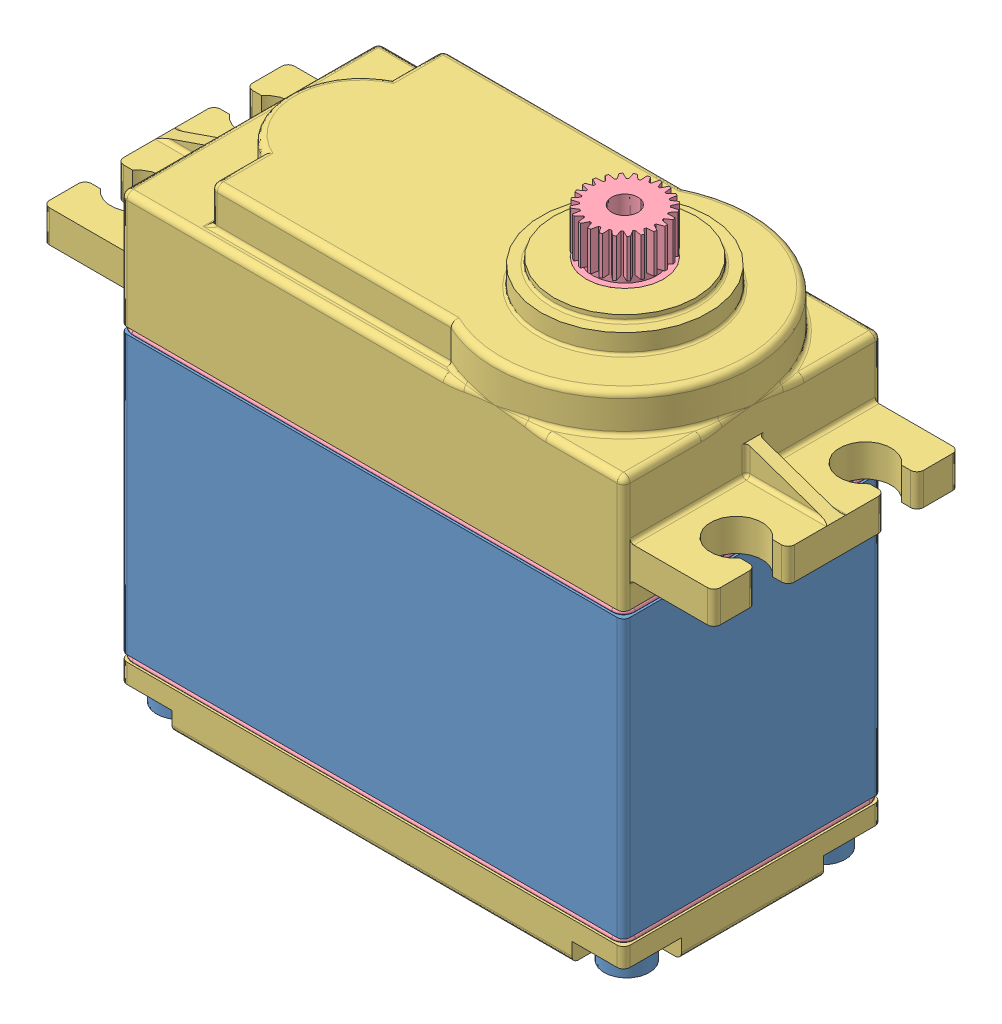
SolidWorks assembly РМ4, configuration По умолчанию. Lengths in mm.
Overall size (52 43 23.81).
64 component instances, 28 part files, 82 mates.
Components (placement in the parent):
- Корпус-2: Корпус [По умолчанию] at origin size (39 28 20)
- Плата-1: Плата [По умолчанию] at (0 -10.5 0) x (-1 0 0) z (0 0 -1) size (37.4 1 18.4)
- Крышка-1: Крышка [По умолчанию] at (0 -13 0) x (-1 0 0) z (0 0 1) size (39 4 20)
- G1-1: G1 [Spur01] at (9.6 15.75 0) x (0.004766 0 0.999989) z (0 1 0) size (17.2 17.2 15.5)
- G2-1: G2 [Spur02] at (-1.2 16.75 0) x (-0.940242 0 0.340506) z (0 1 0) size (6 6 7)
- G3-1: G3 [G3] at (-1.2 19.25 0) x (0.340506 0 0.940242) z (0 1 0) size (13.2 13.2 2)
- G4-1: G4 [G4] at (-9.9 18.5 0) x (-0.495475 0 0.868622) z (0 -1 0) size (5.4 5.4 4)
- G5-1: G5 [G6] at (-9.9 12.5 0) x (0.495475 0 -0.868622) z (0 1 0) size (14.4 14.4 5.5)
- G6-1: G6 [G5] at (-1.2 12 0) x (0.105267 0 -0.994444) z (0 -1 0) size (4.2 4.2 2.5)
- G7-1: G7 [G7] at (-1.2 11.25 0) x (0.994444 0 0.105267) z (0 -1 0) size (15 15 1)
- G8-1: G8 [П8] at (-9.7 11.25 0) x (0.946769 0 0.321915) z (0 -1 0) size (3 3 1)
- Пласт2-1: Пласт2 [По умолчанию] at (9.6 16.5 0) x (0.004766 0 0.999989) z (0.999989 0 -0.004766) size (10 3.05 9.77)
- Пласт1-1: Пласт1 [По умолчанию] at (9.6 14.5 0) x (-0.004766 0 -0.999989) z (0.999989 0 -0.004766) size (7 1.5 9.77)
- Ось-1: Ось [По умолчанию] at (-1.2 15.75 0) x (0.961755 0 0.273911) z (0.273911 0 -0.961755) size (1.5 12.5 1.5)
- Ось1-1: Ось1 [По умолчанию] at (-9.9 18.75 0) x (0.831133 0 0.556074) z (-0.556074 0 0.831133) size (1.5 6.5 1.5)
- Подшипник_1-1: Подшипник_1 [По умолчанию] at (9.6 13.5 0) size (14.01 2 14.01)
  - Вн_кольцо-1: Вн_кольцо [По умолчанию] at origin size (7 2 7)
  - Нар_кольцо-2: Нар_кольцо [По умолчанию] x (0.605705 0 -0.795689) z (0.795689 0 0.605705) size (10 2 10)
  - Шарик-1: Шарик [По умолчанию] at (-3.9953 0 0.1946) size (1.5 1.5 1.5)
  - Шарик-2: Шарик [По умолчанию] at (-3.3466 0 -2.1909) x (0.809017 0 0.587785) z (-0.587785 0 0.809017) size (1.5 1.5 1.5)
  - Шарик-3: Шарик [По умолчанию] at (-1.4197 0 -3.7396) x (0.309017 0 0.951057) z (-0.951057 0 0.309017) size (1.5 1.5 1.5)
  - Шарик-4: Шарик [По умолчанию] at (1.0495 0 -3.8599) x (-0.309017 0 0.951057) z (-0.951057 0 -0.309017) size (1.5 1.5 1.5)
  - Шарик-5: Шарик [По умолчанию] at (3.1179 0 -2.5058) x (-0.809017 0 0.587785) z (-0.587785 0 -0.809017) size (1.5 1.5 1.5)
  - Шарик-6: Шарик [По умолчанию] at (3.9953 0 -0.1946) x (-1 0 0) z (0 0 -1) size (1.5 1.5 1.5)
  - Шарик-7: Шарик [По умолчанию] at (3.3466 0 2.1909) x (-0.809017 0 -0.587785) z (0.587785 0 -0.809017) size (1.5 1.5 1.5)
  - Шарик-8: Шарик [По умолчанию] at (1.4197 0 3.7396) x (-0.309017 0 -0.951057) z (0.951057 0 -0.309017) size (1.5 1.5 1.5)
  - Шарик-9: Шарик [По умолчанию] at (-1.0495 0 3.8599) x (0.309017 0 -0.951057) z (0.951057 0 0.309017) size (1.5 1.5 1.5)
  - Шарик-10: Шарик [По умолчанию] at (-3.1179 0 2.5058) x (0.809017 0 -0.587785) z (0.587785 0 0.809017) size (1.5 1.5 1.5)
- Винт-1: Винт [По умолчанию] at (17.35 0.5 7.6) x (0.946284 0 0.323336) z (0.323336 0 -0.946284) size (3.5 31 3.5)
- Упл_кольцо-1: Упл_кольцо [По умолчанию] at (17.35 -13.5 7.6) x (0.852696 0 0.522408) z (-0.522408 0 0.852696) size (3.2 0.5 3.2)
- Винт-2: Винт [По умолчанию] at (17.35 0 -7.6) x (0.966388 0 0.257088) z (0.257088 0 -0.966388) size (3.5 31 3.5) (suppressed, hidden)
- Упл_кольцо-2: Упл_кольцо [По умолчанию] at (17.35 -14 -7.6) size (3.2 0.5 3.2) (suppressed, hidden)
- Винт-3: Винт [По умолчанию] at (-17.35 0 -7.6) x (-0.966388 0 0.257088) z (0.257088 0 0.966388) size (3.5 31 3.5) (suppressed, hidden)
- Упл_кольцо-3: Упл_кольцо [По умолчанию] at (-17.35 -14 -7.6) x (-1 0 0) z (0 0 -1) size (3.2 0.5 3.2) (suppressed, hidden)
- Упл_кольцо-4: Упл_кольцо [По умолчанию] at (-17.35 -14 7.6) x (-1 0 0) z (0 0 -1) size (3.2 0.5 3.2) (suppressed, hidden)
- Винт-4: Винт [По умолчанию] at (-17.35 0 7.6) x (-0.966388 0 -0.257088) z (-0.257088 0 0.966388) size (3.5 31 3.5) (suppressed, hidden)
- Основание-1: Основание [По умолчанию] at (0 15 0) x (-1 0 0) z (0 0 -1) size (52 14 20.07)
- Подшипник_1-2: Подшипник_1 [По умолчанию] at (9.6 22 0) size (14.01 2 14.01)
  - Вн_кольцо-1: Вн_кольцо [По умолчанию] at origin size (7 2 7)
  - Нар_кольцо-2: Нар_кольцо [По умолчанию] x (0.605705 0 -0.795689) z (0.795689 0 0.605705) size (10 2 10)
  - Шарик-1: Шарик [По умолчанию] at (-3.9953 0 0.1946) size (1.5 1.5 1.5)
  - Шарик-2: Шарик [По умолчанию] at (-3.3466 0 -2.1909) x (0.809017 0 0.587785) z (-0.587785 0 0.809017) size (1.5 1.5 1.5)
  - Шарик-3: Шарик [По умолчанию] at (-1.4197 0 -3.7396) x (0.309017 0 0.951057) z (-0.951057 0 0.309017) size (1.5 1.5 1.5)
  - Шарик-4: Шарик [По умолчанию] at (1.0495 0 -3.8599) x (-0.309017 0 0.951057) z (-0.951057 0 -0.309017) size (1.5 1.5 1.5)
  - Шарик-5: Шарик [По умолчанию] at (3.1179 0 -2.5058) x (-0.809017 0 0.587785) z (-0.587785 0 -0.809017) size (1.5 1.5 1.5)
  - Шарик-6: Шарик [По умолчанию] at (3.9953 0 -0.1946) x (-1 0 0) z (0 0 -1) size (1.5 1.5 1.5)
  - Шарик-7: Шарик [По умолчанию] at (3.3466 0 2.1909) x (-0.809017 0 -0.587785) z (0.587785 0 -0.809017) size (1.5 1.5 1.5)
  - Шарик-8: Шарик [По умолчанию] at (1.4197 0 3.7396) x (-0.309017 0 -0.951057) z (0.951057 0 -0.309017) size (1.5 1.5 1.5)
  - Шарик-9: Шарик [По умолчанию] at (-1.0495 0 3.8599) x (0.309017 0 -0.951057) z (0.951057 0 0.309017) size (1.5 1.5 1.5)
  - Шарик-10: Шарик [По умолчанию] at (-3.1179 0 2.5058) x (0.809017 0 -0.587785) z (0.587785 0 0.809017) size (1.5 1.5 1.5)
- Прокл-1: Прокл [По умолчанию] at (0 -11.75 0) x (1 0 0) z (0 0 1) size (39 0.5 20)
- Прокл-2: Прокл [По умолчанию] at (0 10.25 0) size (39 0.5 20)
- Винт-8: Винт [По умолчанию] at (17.35 0.5 -7.6) x (0.946284 0 0.323336) z (0.323336 0 -0.946284) size (3.5 31 3.5)
- Упл_кольцо-5: Упл_кольцо [По умолчанию] at (17.35 -13.5 -7.6) x (0.852696 0 0.522408) z (-0.522408 0 0.852696) size (3.2 0.5 3.2)
- Винт-9: Винт [По умолчанию] at (-17.35 0.5 7.6) x (0.946284 0 0.323336) z (0.323336 0 -0.946284) size (3.5 31 3.5)
- Упл_кольцо-6: Упл_кольцо [По умолчанию] at (-17.35 -13.5 7.6) x (0.852696 0 0.522408) z (-0.522408 0 0.852696) size (3.2 0.5 3.2)
- Винт-10: Винт [По умолчанию] at (-17.35 0.5 -7.6) x (0.946284 0 0.323336) z (0.323336 0 -0.946284) size (3.5 31 3.5)
- Упл_кольцо-7: Упл_кольцо [По умолчанию] at (-17.35 -13.5 -7.6) x (0.852696 0 0.522408) z (-0.522408 0 0.852696) size (3.2 0.5 3.2)
- Штырь-1: Штырь [По умолчанию] at (16.0999 17 -0.031) x (-0.26515 0 -0.964207) z (0.964207 0 -0.26515) size (2 7 2)
- Дв_корп-1: Дв_корп [По умолчанию] at (-9.7 0 0) size (17.2 18 17.2)
- Дв_вал-1: Дв_вал [По умолчанию] at (-9.7 7 0) size (1 10 1)
- Дв_крышка-1: Дв_крышка [По умолчанию] at (-9.7 -9.5 0) x (-0.837169 0 -0.546944) z (-0.546944 0 0.837169) size (17.2 2 17.2)
- Птнц_корп-1: Птнц_корп [По умолчанию] at (9.6 5 0) size (10 4 10)
- Птнц_вал-1: Птнц_вал [По умолчанию] at (9.6 12.5 0) x (-0.004766 0 -0.999989) z (0.999989 0 -0.004766) size (4 11 4)
Mates (geometry in assembly coordinates):
- Совпадение7: coincident anti-aligned: plane of Корпус-2 through (0 -10 -32.5618) normal (0 -1 0); plane of Плата-1 through (32.5618 -10 0) normal (0 1 0)
- Совпадение8: coincident anti-aligned: plane of Корпус-2 through (19.5 -11 -9.2) normal (0 0 1); plane of Плата-1 through (32.5618 -10 -9.2) normal (0 0 -1)
- Совпадение9: coincident anti-aligned: plane of Корпус-2 through (18.7 -11 -10) normal (-1 0 0); plane of Плата-1 through (18.7 -10 0) normal (1 0 0)
- Совпадение10: coincident anti-aligned: plane of Корпус-2 through (18.7 -11 -9.2) normal (0 -1 0); plane of Крышка-1 through (19.5 -11 -10) normal (0 1 0)
- Совпадение12: coincident anti-aligned: plane of Корпус-2 through (19.5 -11 -9.2) normal (0 0 1); plane of Крышка-1 through (-18.7 -12 -9.2) normal (0 0 -1)
- Совпадение13: coincident anti-aligned: plane of Корпус-2 through (-18.7 -11 -10) normal (1 0 0); plane of Крышка-1 through (-18.7 -12 9.2) normal (-1 0 0)
- Концентричный1: concentric aligned: cylinder of G2-1 through (-1.2 18.25 0) axis (0 1 0) radius 2.5; cylinder of G3-1 through (-1.2 11.1789 0) axis (0 1 0) radius 2.5
- Совпадение14: coincident anti-aligned: plane of G2-1 through (-1.2 18.25 0) normal (0 1 0); plane of G3-1 through (5.0056 18.25 -2.2473) normal (0 -1 0)
- Концентричный2: concentric anti-aligned: cylinder of G4-1 through (-9.9 17.5 0) axis (0 -1 0) radius 2.4; cylinder of G5-1 through (-9.9 9.7118 0) axis (0 1 0) radius 2.4
- Совпадение15: coincident anti-aligned: plane of G4-1 through (-9.9 17.5 0) normal (0 -1 0); plane of G5-1 through (-9.9 17.5 0) normal (0 1 0)
- Концентричный3: concentric aligned: cylinder of G6-1 through (-1.2 11.75 0) axis (0 -1 0) radius 1.75; cylinder of G7-1 through (-1.2 16.6997 0) axis (0 -1 0) radius 1.75
- Совпадение16: coincident anti-aligned: plane of G6-1 through (-7.904 11.75 -0.7097) normal (0 -1 0); plane of G7-1 through (-1.9895 11.75 7.4583) normal (0 1 0)
- Концентричный4: concentric anti-aligned: cylinder of Пласт2-1 through (9.6 8.4289 0) axis (0 1 0) radius 2.5; cylinder of Пласт1-1 through (9.6 16 0) axis (0 -1 0) radius 2.5
- Концентричный5: concentric anti-aligned: cylinder of Пласт2-1 through (4.6001 14.5 0.0238) axis (0 1 0) radius 1.5; cylinder of Пласт1-1 through (4.6001 15.5 0.0238) axis (0 -1 0) radius 1.5
- Совпадение17: coincident anti-aligned: plane of Пласт2-1 through (9.66 15.5 -11.0188) normal (0 -1 0); plane of Пласт1-1 through (9.6282 15.5 11.1805) normal (0 1 0)
- Концентричный6: concentric aligned: cylinder of G1-1 through (9.6 19 0) axis (0 -1 0) radius 3; cylinder of Пласт2-1 through (9.6 17.5 0) axis (0 -1 0) radius 3
- Совпадение18: coincident aligned: plane of G1-1; plane of Пласт2-1
- Совпадение19: coincident anti-aligned: plane of G1-1 through (9.6 16.5 0) normal (0 -1 0); plane of Пласт2-1 through (9.5216 16.5 -11.1803) normal (0 1 0)
- Концентричный7: concentric anti-aligned: cylinder of G6-1 through (-1.2 15.3713 0) axis (0 -1 0) radius 0.75; cylinder of Ось-1 through (-1.2 9.5 0) axis (0 1 0) radius 0.75
- Совпадение21: coincident aligned: plane of G7-1 through (-1.2 11.25 0) normal (0 -1 0); plane of G8-1 through (-9.7 11.25 0) normal (0 -1 0)
- Совпадение23: coincident: line of G7-1 through (-1.2 -43.75 0) axis (0 1 0); plane of assembly
- Совпадение25: coincident anti-aligned: plane of Корпус-2 through (-1.2 9.5 0) normal (0 1 0); plane of Ось-1 through (-1.2 9.5 0) normal (0 -1 0)
- Совпадение26: coincident anti-aligned: plane of Корпус-2 through (-30.4875 10.75 0) normal (0 1 0); plane of G6-1 through (-1.2 10.75 0) normal (0 -1 0)
- Концентричный8: concentric aligned: cylinder of Корпус-2 through (-1.2 9.5 0) axis (0 1 0) radius 0.75; cylinder of Ось-1 through (-1.2 9.5 0) axis (0 1 0) radius 0.75
- Концентричный9: concentric aligned: cylinder of G4-1 through (-9.9 18.5 0) axis (0 -1 0) radius 0.75; cylinder of Ось1-1 through (-9.9 22 0) axis (0 -1 0) radius 0.75
- Совпадение32: coincident aligned: plane of G6-1; plane of G7-1
- Совпадение33: coincident anti-aligned: plane of G4-1; plane of G5-1
- Концентричный10: concentric aligned: cylinder of G2-1 through (-1.2 11.1287 0) axis (0 1 0) radius 0.75; cylinder of Ось-1 through (-1.2 9.5 0) axis (0 1 0) radius 0.75
- Совпадение34: coincident anti-aligned: plane of G2-1 through (-0.1785 13.25 2.8207) normal (0 -1 0); plane of G6-1 through (0.8883 13.25 0.2211) normal (0 1 0)
- Совпадение35: coincident anti-aligned: plane of G2-1; plane of G3-1
- Концентричный11: concentric aligned: cylinder of Корпус-2 through (9.6 14.5 0) axis (0 -1 0) radius 3; cylinder of Подшипник_1-1/Вн_кольцо-1 through (9.6 14.5 0) axis (0 -1 0) radius 3
- Совпадение36: coincident anti-aligned: plane of Корпус-2 through (9.6 12.5 0) normal (0 1 0); plane of Подшипник_1-1/Вн_кольцо-1 through (9.6 12.5 0) normal (0 -1 0)
- Концентричный13: concentric aligned: cylinder of G1-1 through (9.6 16.5 0) axis (0 -1 0) radius 5; cylinder of Подшипник_1-1/Нар_кольцо-2 through (9.6 14.5 0) axis (0 -1 0) radius 5
- Совпадение39: coincident anti-aligned: plane of Пласт1-1 through (9.6282 14.5 11.1805) normal (0 -1 0); plane of Подшипник_1-1/Нар_кольцо-2 through (9.6 14.5 0) normal (0 1 0)
- Сопряжения редуктора5: gear = 5.2 : 16.4 mm: circle of G1-1; circle of G2-1
- Совпадение40: coincident anti-aligned: plane of Корпус-2 through (-14.4414 15.5 0) normal (0 1 0); plane of Ось1-1 through (-9.9 15.5 0) normal (0 -1 0)
- Концентричный16: concentric anti-aligned: cylinder of Корпус-2 through (-9.9 15.5 0) axis (0 1 0) radius 0.75; cylinder of Ось1-1 through (-9.9 22 0) axis (0 -1 0) radius 0.75
- Совпадение41: coincident anti-aligned: plane of Корпус-2 through (-17.7642 16.5 0) normal (0 1 0); plane of G4-1 through (-9.9 16.5 0) normal (0 -1 0)
- Концентричный19: concentric aligned: cylinder of Корпус-2 through (-9.7 11.9142 0) axis (0 -1 0) radius 0.5; circle of G8-1
- Сопряжения редуктора6: gear = 2.5 : 14.5 mm: circle of G7-1; circle of G8-1
- Сопряжения редуктора7: gear = 3.6 : 13.8 mm: circle of G5-1; circle of G6-1
- Сопряжения редуктора8: gear = 4.8 : 12.6 mm: circle of G3-1; circle of G4-1
- Концентричный20: concentric aligned: cylinder of Крышка-1 through (17.35 -13 7.6) axis (0 -1 0) radius 1.6; cylinder of Упл_кольцо-1 through (17.35 -13 7.6) axis (0 -1 0) radius 1.6
- Совпадение43: coincident anti-aligned: plane of Винт-1 through (17.35 -13.5 7.6) normal (0 1 0); plane of Упл_кольцо-1 through (17.35 -13.5 7.6) normal (0 -1 0)
- Концентричный24: concentric aligned: cylinder of Крышка-1 through (17.35 -8.1716 7.6) axis (0 -1 0) radius 1; cylinder of Винт-1 through (17.35 -15 7.6) axis (0 -1 0) radius 0.8
- Совпадение48: coincident anti-aligned: plane of Основание-1 through (0 15 0) normal (0 0 -1); plane of assembly through (0 0 0) normal (0 0 1)
- Концентричный25: concentric aligned: cylinder of Основание-1 through (9.6 23 0) axis (0 -1 0) radius 5; cylinder of Подшипник_1-2/Нар_кольцо-2 through (9.6 23 0) axis (0 -1 0) radius 5
- Совпадение49: coincident anti-aligned: plane of Основание-1 through (9.6 23 0) normal (0 -1 0); plane of Подшипник_1-2/Нар_кольцо-2 through (9.6 23 0) normal (0 1 0)
- Совпадение50: coincident anti-aligned: plane of Основание-1 through (0 15 0) normal (-1 0 0); plane of assembly through (0 0 0) normal (1 0 0)
- Касательность1: tangent: plane of Корпус-2 through (19.5 -11.5 -10) normal (0 -1 0); face of Прокл-1
- Касательность2: tangent: plane of Крышка-1 through (18.7 -12 -9.2) normal (1 0 0); face of Прокл-1
- Касательность3: tangent: plane of Крышка-1 through (-18.7 -12 -9.2) normal (0 0 -1); face of Прокл-1
- Совпадение51: coincident anti-aligned: plane of Корпус-2 through (19.5 11.5 -10) normal (0 1 0); plane of Основание-1 through (-18.7 11.5 9.2) normal (0 -1 0)
- Совпадение52: coincident aligned: plane of Корпус-2 through (0 0 0) normal (0 0 1); plane of Прокл-2 through (0 10.25 0) normal (0 0 1)
- Совпадение53: coincident aligned: plane of Корпус-2 through (0 0 0) normal (1 0 0); plane of Прокл-2 through (0 10.25 0) normal (1 0 0)
- Расстояние1: distance = 0.25 mm aligned: plane of Корпус-2 through (-34.2325 10 0) normal (0 1 0); plane of Прокл-2 through (0 10.25 0) normal (0 1 0)
- Совпадение58: coincident anti-aligned: plane of Крышка-1 through (17.35 -13 7.6) normal (0 -1 0); plane of Упл_кольцо-1 through (17.35 -13 7.6) normal (0 1 0)
- Совпадение59: coincident anti-aligned: plane of Винт-8 through (17.35 -13.5 -7.6) normal (0 1 0); plane of Упл_кольцо-5 through (17.35 -13.5 -7.6) normal (0 -1 0)
- Концентричный29: concentric aligned: cylinder of Крышка-1 through (17.35 -13 -7.6) axis (0 -1 0) radius 1.6; cylinder of Упл_кольцо-5 through (17.35 -13 -7.6) axis (0 -1 0) radius 1.6
- Концентричный30: concentric aligned: cylinder of Крышка-1 through (17.35 -8.1716 -7.6) axis (0 -1 0) radius 1; cylinder of Винт-8 through (17.35 -15 -7.6) axis (0 -1 0) radius 0.8
- Совпадение60: coincident anti-aligned: plane of Крышка-1 through (17.35 -13 -7.6) normal (0 -1 0); plane of Упл_кольцо-5 through (17.35 -13 -7.6) normal (0 1 0)
- Совпадение61: coincident anti-aligned: plane of Винт-9 through (-17.35 -13.5 7.6) normal (0 1 0); plane of Упл_кольцо-6 through (-17.35 -13.5 7.6) normal (0 -1 0)
- Концентричный31: concentric aligned: cylinder of Крышка-1 through (-17.35 -13 7.6) axis (0 -1 0) radius 1.6; cylinder of Упл_кольцо-6 through (-17.35 -13 7.6) axis (0 -1 0) radius 1.6
- Концентричный32: concentric aligned: cylinder of Крышка-1 through (-17.35 -8.1716 7.6) axis (0 -1 0) radius 1; cylinder of Винт-9 through (-17.35 -15 7.6) axis (0 -1 0) radius 0.8
- Совпадение62: coincident anti-aligned: plane of Крышка-1 through (-17.35 -13 7.6) normal (0 -1 0); plane of Упл_кольцо-6 through (-17.35 -13 7.6) normal (0 1 0)
- Совпадение63: coincident anti-aligned: plane of Винт-10 through (-17.35 -13.5 -7.6) normal (0 1 0); plane of Упл_кольцо-7 through (-17.35 -13.5 -7.6) normal (0 -1 0)
- Концентричный33: concentric aligned: cylinder of Крышка-1 through (-17.35 -13 -7.6) axis (0 -1 0) radius 1.6; cylinder of Упл_кольцо-7 through (-17.35 -13 -7.6) axis (0 -1 0) radius 1.6
- Концентричный34: concentric aligned: cylinder of Крышка-1 through (-17.35 -8.1716 -7.6) axis (0 -1 0) radius 1; cylinder of Винт-10 through (-17.35 -15 -7.6) axis (0 -1 0) radius 0.8
- Совпадение64: coincident anti-aligned: plane of Крышка-1 through (-17.35 -13 -7.6) normal (0 -1 0); plane of Упл_кольцо-7 through (-17.35 -13 -7.6) normal (0 1 0)
- Концентричный35: concentric anti-aligned: cylinder of G1-1 through (16.0999 9.6716 -0.031) axis (0 1 0) radius 1; cylinder of Штырь-1 through (16.0999 20.5 -0.031) axis (0 -1 0) radius 1
- Совпадение65: coincident aligned: plane of G1-1 through (18.1999 13.5 -0.041) normal (0 -1 0); plane of Штырь-1 through (16.0999 13.5 -0.031) normal (0 -1 0)
- Совпадение66: coincident anti-aligned: plane of Корпус-2 through (0 9 -33.3273) normal (0 -1 0); plane of Дв_корп-1 through (-10.2 9 0) normal (0 1 0)
- Концентричный36: concentric aligned: cylinder of Дв_корп-1 through (-9.7 -16.8719 0) axis (0 -1 0) radius 0.5; cylinder of Дв_вал-1 through (-9.7 12 0) axis (0 -1 0) radius 0.5
- Расстояние2: distance = 3 mm aligned: plane of Дв_вал-1 through (-9.7 12 0) normal (0 1 0); plane of Дв_корп-1 through (-10.2 9 0) normal (0 1 0)
- Концентричный37: concentric aligned: cylinder of G8-1 through (-9.7 13.1642 0) axis (0 -1 0) radius 0.5; cylinder of Дв_вал-1 through (-9.7 12 0) axis (0 -1 0) radius 0.5
- Концентричный38: concentric anti-aligned: cylinder of Дв_корп-1 through (-9.7 -16.8719 0) axis (0 -1 0) radius 7.6; cylinder of Дв_крышка-1 through (-9.7 -9 0) axis (0 1 0) radius 7.6
- Совпадение67: coincident anti-aligned: plane of Плата-1 through (32.5618 -10 0) normal (0 1 0); plane of Дв_крышка-1 through (-9.7 -10 0) normal (0 -1 0)
- Концентричный41: concentric anti-aligned: cylinder of Птнц_корп-1 through (9.6 7 0) axis (0 1 0) radius 2; cylinder of Птнц_вал-1 through (9.6 18 0) axis (0 -1 0) radius 2
- Концентричный42: concentric anti-aligned: cylinder of Корпус-2 through (9.6 3.3431 0) axis (0 1 0) radius 2; cylinder of Птнц_вал-1 through (9.6 18 0) axis (0 -1 0) radius 2
- Совпадение71: coincident anti-aligned: plane of Корпус-2 through (0 9 -33.3273) normal (0 -1 0); plane of Птнц_корп-1 through (4.6 9 0) normal (0 1 0)
- Совпадение72: coincident anti-aligned: plane of Пласт1-1 through (8.6269 10.0279 5.6461) normal (0.999989 0 -0.004766); plane of Птнц_вал-1 through (8.6095 16 2.0057) normal (-0.999989 0 0.004766)
- Совпадение73: coincident anti-aligned: plane of Птнц_корп-1 through (7.6 7 0) normal (0 1 0); plane of Птнц_вал-1 through (9.6 7 0) normal (0 -1 0)
